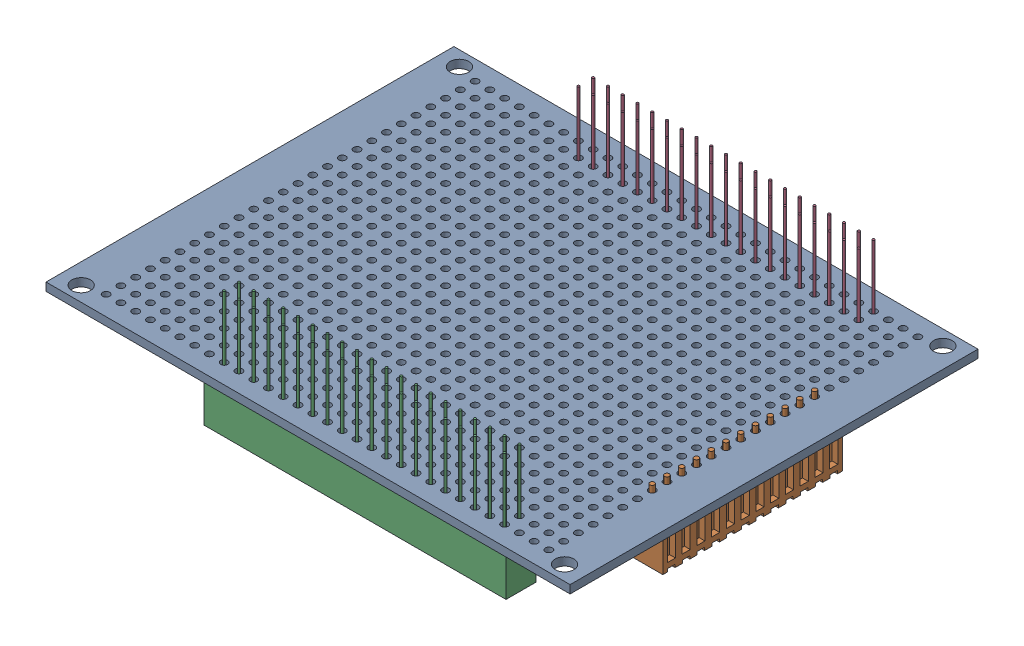
SolidWorks assembly encoderBoard, configuration Default. Lengths in mm.
Overall size (90.2 20.9 70.2).
4 component instances, 3 part files, 9 mates.
Components (placement in the parent):
- board-1: board [Default] at origin size (90.2 1.4 70.2)
- terminalBlock_12Pin-1: terminalBlock_12Pin [Default] at (38.25 0 0) x (0 0 1) z (1 0 0) size (30.88 11.2 6.3)
- femaleHeader_20pin-3: femaleHeader_20pin [Default] at (6.05 0 30.48) x (-1 0 0) z (0 0 1) size (52 20.45 5.2)
- femaleHeader_20pin-4: femaleHeader_20pin [Default] at (6.05 0 -30.48) x (-1 0 0) z (0 0 1) size (52 20.45 5.2)
Mates (geometry in assembly coordinates):
- Concentric7: concentric anti-aligned: cylinder of board-1 through (30.48 0 31.75) axis (0 1 0) radius 0.6; cylinder of femaleHeader_20pin-3 through (30.48 12.1 31.75) axis (0 -1 0) radius 0.2
- Concentric8: concentric anti-aligned: cylinder of board-1 through (30.48 0 29.21) axis (0 1 0) radius 0.6; cylinder of femaleHeader_20pin-3 through (30.48 12.1 29.21) axis (0 -1 0) radius 0.2
- Coincident4: coincident anti-aligned: plane of board-1 through (0 0 0) normal (0 -1 0); plane of femaleHeader_20pin-3 through (6.05 0 30.48) normal (0 1 0)
- Concentric9: concentric anti-aligned: cylinder of board-1 through (30.48 0 -31.75) axis (0 1 0) radius 0.6; cylinder of femaleHeader_20pin-4 through (30.48 12.1 -31.75) axis (0 -1 0) radius 0.2
- Concentric10: concentric anti-aligned: cylinder of board-1 through (30.48 0 -29.21) axis (0 1 0) radius 0.6; cylinder of femaleHeader_20pin-4 through (30.48 12.1 -29.21) axis (0 -1 0) radius 0.2
- Coincident5: coincident anti-aligned: plane of board-1 through (0 0 0) normal (0 -1 0); plane of femaleHeader_20pin-4 through (6.05 0 -30.48) normal (0 1 0)
- Coincident7: coincident: plane of board-1 through (0 0 0) normal (0 -1 0); plane of terminalBlock_12Pin-1 through (37.9836 0 0.0003) normal (0 1 0)
- Concentric13: concentric: cylinder of board-1 through (38.1 0 -13.97) axis (0 1 0) radius 0.6; cylinder of terminalBlock_12Pin-1 through (38.1 2.4 -13.97) axis (0 -1 0) radius 0.4
- Concentric14: concentric anti-aligned: cylinder of board-1 through (38.1 0 -11.43) axis (0 1 0) radius 0.6; cylinder of terminalBlock_12Pin-1 through (38.1 2.4 -11.43) axis (0 -1 0) radius 0.4
